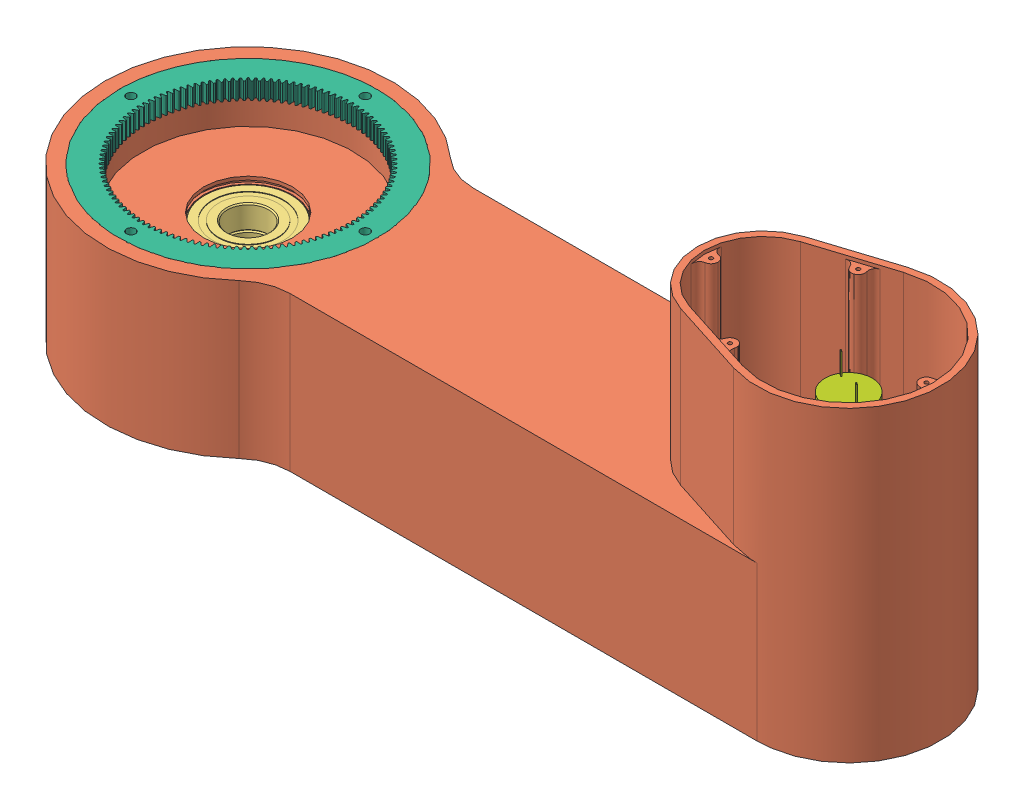
SolidWorks assembly Wall Link Assembly, configuration Default. Lengths in mm.
Overall size (388.62 146.05 133.35).
31 component instances, 11 part files, 33 mates.
Components (placement in the parent):
- magnet holder-1: magnet holder [Default] at (-69.5408 -3.8692 23.5746) x (-0.081084 0 0.996707) z (-0.996707 0 -0.081084) size (50.8 63.9 50.6)
- Wall Link Frame-1: Wall Link Frame [Default] at (-348.6164 39.6281 19.5878) x (1 0 0) z (0 -1 0) size (388.62 133.35 142.88)
- Bearing - .750-1: Bearing - .750 [3760T241] at (-69.2164 21.7681 19.5878) x (0.982823 0 0.184551) z (0 -1 0) size (41.27 41.27 11.11)
- Bearing - .750-2: Bearing - .750 [3760T241] at (-69.2164 32.8806 19.5878) x (0.837169 0 0.546944) z (0 1 0) size (41.27 41.27 11.11)
- Bearing - .750-3: Bearing - .750 [3760T241] at (-348.6164 6.5421 19.5878) x (0.79819 0 0.602406) z (0 1 0) size (41.27 41.27 11.11)
- Bearing - .750-4: Bearing - .750 [3760T241] at (-348.6164 17.6546 19.5878) x (0.713431 0 0.700725) z (0 1 0) size (41.27 41.27 11.11)
- Magnet Encoders E3-X-750-X-H-D-X-1: Magnet Encoders E3-X-750-X-H-D-X [Default] at (-69.2164 52.5821 19.5878) x (0 0 1) z (-1 0 0) size (55.98 16.26 66.52)
- EM237 Magnet-1: EM237 Magnet [Default] at (-69.2164 -16.3787 19.5878) x (0.767455 0 -0.641103) z (-0.641103 0 -0.767455) size (60.08 25.02 60.08)
- Ring Gear-1: Ring Gear [Default] at (-348.6168 41.9781 19.5878) x (0 -1 0) z (0 0 1) size (8 120 120)
- Magnet Encoders E3-X-750-X-H-D-X-2: Magnet Encoders E3-X-750-X-H-D-X [Default] at (-348.6164 -5.6182 19.5878) x (0 0 1) z (1 0 0) size (55.98 16.26 66.52)
- Slip Ring M322M1-0202-1: Slip Ring M322M1-0202 [Default] at (-69.2164 73.1741 19.5878) x (0.866025 0 0.5) z (0 -1 0) size (44 44 57)
- M5 Nylon Spacer-1: M5 Nylon Spacer [93657A042] at (-60.4664 67.7741 34.7433) x (0.837169 0 0.546944) z (0 -1 0) size (8 8 6)
- M5 Nylon Spacer-2: M5 Nylon Spacer [93657A042] at (-60.4664 67.7741 4.4324) x (0.552857 0 0.833276) z (0 -1 0) size (8 8 6)
- M5 Nylon Spacer-3: M5 Nylon Spacer [93657A042] at (-86.7164 67.7741 19.5878) x (0.837169 0 0.546944) z (0 -1 0) size (8 8 6)
- PCB_Battery Assembly-1: PCB_Battery Assembly [Default] at (-108.4133 -78.6819 -2.0435) size (127.38 21.9 77.22)
  - Battery PCB-1: Battery PCB [Default] at (-148.3186 115.135 -16.9005) x (1 0 0) z (0 -1 0) size (127.38 77.06 1.59)
  - Battery Assembly-1: Battery Assembly [Default] at (-101.6605 145.5711 -35.2548) x (-1 0 0) z (0 0 1) size (20.65 21.9 77.14)
    - Battery Holder - keystone-PN1043-1: Battery Holder - keystone-PN1043 [Default] at (27.979 42.1729 59.6018) size (20.65 18.93 77.14)
    - battery_6612-1: battery_6612 [Default] at (36.333 41.1675 88.8909) x (1 0 0) z (0 1 0) size (18.3 65.05 18.3)
  - Battery Assembly-2: Battery Assembly [Default] at (-130.4862 145.5711 78.5174) x (1 0 0) z (0 0 -1) size (20.65 21.9 77.14)
    - Battery Holder - keystone-PN1043-1: Battery Holder - keystone-PN1043 [Default] at (27.979 42.1729 59.6018) size (20.65 18.93 77.14)
    - battery_6612-1: battery_6612 [Default] at (36.333 41.1675 88.8909) x (1 0 0) z (0 1 0) size (18.3 65.05 18.3)
  - Battery Assembly-3: Battery Assembly [Default] at (-13.9797 145.5711 -35.2548) x (-1 0 0) z (0 0 1) size (20.65 21.9 77.14)
    - Battery Holder - keystone-PN1043-1: Battery Holder - keystone-PN1043 [Default] at (27.979 42.1729 59.6018) size (20.65 18.93 77.14)
    - battery_6612-1: battery_6612 [Default] at (36.333 41.1675 88.8909) x (1 0 0) z (0 1 0) size (18.3 65.05 18.3)
  - Battery Assembly-4: Battery Assembly [Default] at (-108.566 145.5711 78.5174) x (1 0 0) z (0 0 -1) size (20.65 21.9 77.14)
    - Battery Holder - keystone-PN1043-1: Battery Holder - keystone-PN1043 [Default] at (27.979 42.1729 59.6018) size (20.65 18.93 77.14)
    - battery_6612-1: battery_6612 [Default] at (36.333 41.1675 88.8909) x (1 0 0) z (0 1 0) size (18.3 65.05 18.3)
  - Battery Assembly-5: Battery Assembly [Default] at (-79.7403 145.5711 -35.2548) x (-1 0 0) z (0 0 1) size (20.65 21.9 77.14)
    - Battery Holder - keystone-PN1043-1: Battery Holder - keystone-PN1043 [Default] at (27.979 42.1729 59.6018) size (20.65 18.93 77.14)
    - battery_6612-1: battery_6612 [Default] at (36.333 41.1675 88.8909) x (1 0 0) z (0 1 0) size (18.3 65.05 18.3)
Mates (geometry in assembly coordinates):
- Concentric2: concentric anti-aligned: line of Wall Link Frame-1 through (-69.2164 -25.7134 19.5878) axis (0 1 0); cylinder of Bearing - .750-1 through (-69.2164 16.2118 19.5878) axis (0 -1 0) radius 9.525
- Coincident1: coincident aligned: plane of Wall Link Frame-1 through (-348.6164 16.2118 19.5878) normal (0 -1 0); plane of Bearing - .750-1 through (-72.9226 16.2118 39.3247) normal (0 -1 0)
- Concentric3: concentric aligned: line of Wall Link Frame-1 through (-69.2164 -25.7134 19.5878) axis (0 1 0); cylinder of Bearing - .750-2 through (-69.2164 38.4368 19.5878) axis (0 1 0) radius 9.525
- Coincident2: coincident anti-aligned: plane of Bearing - .750-1 through (-72.9226 27.3243 39.3247) normal (0 1 0); plane of Bearing - .750-2 through (-58.2328 27.3243 2.7759) normal (0 -1 0)
- Concentric4: concentric anti-aligned: cylinder of magnet holder-1 through (-69.2164 -3.8692 19.5878) axis (0 -1 0) radius 9.525; cylinder of Bearing - .750-2 through (-69.2164 38.4368 19.5878) axis (0 1 0) radius 9.525
- Coincident3: coincident anti-aligned: plane of magnet holder-1 through (-70.2462 16.2118 32.246) normal (0 1 0); plane of Wall Link Frame-1 through (-348.6164 16.2118 19.5878) normal (0 -1 0)
- Concentric5: concentric aligned: line of Wall Link Frame-1 through (-69.2164 -25.7134 19.5878) axis (0 1 0); cylinder of Magnet Encoders E3-X-750-X-H-D-X-1 through (-69.2164 59.1353 19.5878) axis (0 1 0) radius 9.5263
- Concentric6: concentric anti-aligned: cylinder of Wall Link Frame-1 through (-69.2164 49.1531 42.6002) axis (0 1 0) radius 1.1303; cylinder of Magnet Encoders E3-X-750-X-H-D-X-1 through (-69.2164 52.5821 42.6002) axis (0 -1 0) radius 1.4351
- Coincident7: coincident anti-aligned: plane of Wall Link Frame-1 through (-348.6164 49.1531 19.5878) normal (0 1 0); plane of Magnet Encoders E3-X-750-X-H-D-X-1 through (-69.2164 49.1531 19.5878) normal (0 -1 0)
- Coincident8: coincident anti-aligned: plane of magnet holder-1 through (-69.5408 -3.8692 23.5746) normal (0 -1 0); plane of EM237 Magnet-1 through (-69.2164 -3.8692 19.5878) normal (0 1 0)
- Concentric7: concentric aligned: line of Wall Link Frame-1 through (-69.2164 -25.7134 19.5878) axis (0 1 0); cylinder of EM237 Magnet-1 through (-69.2164 -3.8692 19.5878) axis (0 1 0) radius 3.4036
- Coincident9: coincident anti-aligned: line of Wall Link Frame-1 through (-348.6164 -48.2167 19.5878) axis (0 1 0); line of Ring Gear-1 through (-348.6168 45.9781 19.5878) axis (0 -1 0)
- Coincident10: coincident anti-aligned: plane of Wall Link Frame-1 through (-348.6164 37.9781 19.5878) normal (0 1 0); plane of Ring Gear-1 through (-348.6168 37.9781 19.5878) normal (0 -1 0)
- Concentric8: concentric anti-aligned: cylinder of Wall Link Frame-1 through (-294.1114 37.9781 19.5878) axis (0 1 0) radius 1.7272; cylinder of Ring Gear-1 through (-294.1114 45.9781 19.5878) axis (0 -1 0) radius 2.0828
- Coincident11: coincident anti-aligned: plane of Wall Link Frame-1 through (-369.2539 0.9858 19.5878) normal (0 1 0); plane of Bearing - .750-3 through (-336.519 0.9858 3.5587) normal (0 -1 0)
- Concentric9: concentric aligned: line of Wall Link Frame-1 through (-348.6164 -48.2167 19.5878) axis (0 1 0); cylinder of Bearing - .750-3 through (-348.6164 12.0983 19.5878) axis (0 1 0) radius 9.525
- Concentric10: concentric aligned: cylinder of Bearing - .750-4 through (-348.6164 23.2108 19.5878) axis (0 1 0) radius 9.525; line of Wall Link Frame-1 through (-348.6164 -48.2167 19.5878) axis (0 1 0)
- Coincident13: coincident anti-aligned: plane of Bearing - .750-3 through (-336.519 12.0983 3.5587) normal (0 1 0); plane of Bearing - .750-4 through (-334.5446 12.0983 5.2608) normal (0 -1 0)
- Coincident14: coincident anti-aligned: plane of Wall Link Frame-1 through (-364.4914 -2.1892 19.5878) normal (0 -1 0); plane of Magnet Encoders E3-X-750-X-H-D-X-2 through (-348.6164 -2.1892 19.5878) normal (0 1 0)
- Concentric12: concentric anti-aligned: cylinder of Wall Link Frame-1 through (-348.6164 -2.1892 42.6002) axis (0 -1 0) radius 1.1303; cylinder of Magnet Encoders E3-X-750-X-H-D-X-2 through (-348.6164 -5.6182 42.6002) axis (0 1 0) radius 1.4351
- Concentric13: concentric anti-aligned: cylinder of Wall Link Frame-1 through (-348.6164 -2.1892 -3.4246) axis (0 -1 0) radius 1.1303; cylinder of Magnet Encoders E3-X-750-X-H-D-X-2 through (-348.6164 -5.6182 -3.4246) axis (0 1 0) radius 1.4351
- Concentric14: concentric aligned: cylinder of magnet holder-1 through (-69.2164 -3.8692 19.5878) axis (0 -1 0) radius 6.7469; cylinder of Slip Ring M322M1-0202-1 through (-69.2164 93.7741 19.5878) axis (0 -1 0) radius 11
- Concentric15: concentric aligned: cylinder of Magnet Encoders E3-X-750-X-H-D-X-1 through (-86.7164 64.7741 19.5878) axis (0 1 0) radius 2.1; cylinder of M5 Nylon Spacer-3 through (-86.7164 64.7741 19.5878) axis (0 1 0) radius 2.65
- Concentric16: concentric aligned: cylinder of Magnet Encoders E3-X-750-X-H-D-X-1 through (-60.4664 64.7741 34.7433) axis (0 1 0) radius 2.1; cylinder of M5 Nylon Spacer-1 through (-60.4664 64.7741 34.7433) axis (0 1 0) radius 2.65
- Concentric17: concentric aligned: cylinder of Magnet Encoders E3-X-750-X-H-D-X-1 through (-60.4664 64.7741 4.4324) axis (0 1 0) radius 2.1; cylinder of M5 Nylon Spacer-2 through (-60.4664 64.7741 4.4324) axis (0 1 0) radius 2.65
- Coincident16: coincident anti-aligned: plane of Magnet Encoders E3-X-750-X-H-D-X-1 through (-69.2164 64.7741 19.5878) normal (0 1 0); plane of M5 Nylon Spacer-2 through (-60.4664 64.7741 4.4324) normal (0 -1 0)
- Coincident17: coincident anti-aligned: plane of Magnet Encoders E3-X-750-X-H-D-X-1 through (-69.2164 64.7741 19.5878) normal (0 1 0); plane of M5 Nylon Spacer-1 through (-60.4664 64.7741 34.7433) normal (0 -1 0)
- Coincident18: coincident anti-aligned: plane of Magnet Encoders E3-X-750-X-H-D-X-1 through (-69.2164 64.7741 19.5878) normal (0 1 0); plane of M5 Nylon Spacer-3 through (-86.7164 64.7741 19.5878) normal (0 -1 0)
- Concentric19: concentric aligned: cylinder of Magnet Encoders E3-X-750-X-H-D-X-1 through (-86.7164 64.7741 19.5878) axis (0 1 0) radius 2.1; cylinder of Slip Ring M322M1-0202-1 through (-86.7164 73.1741 19.5878) axis (0 1 0) radius 2.75
- Coincident19: coincident anti-aligned: plane of Slip Ring M322M1-0202-1 through (-50.1639 70.7741 30.5878) normal (0 -1 0); plane of M5 Nylon Spacer-3 through (-86.7164 70.7741 19.5878) normal (0 1 0)
- Concentric20: concentric anti-aligned: cylinder of Wall Link Frame-1 through (-142.0509 36.4531 51.7696) axis (0 -1 0) radius 0.889; cylinder of PCB_Battery Assembly-1/Battery PCB-1 through (-142.0509 34.8656 51.7696) axis (0 1 0) radius 1.651
- Concentric23: concentric anti-aligned: cylinder of Wall Link Frame-1 through (-263.0819 36.4531 51.7696) axis (0 -1 0) radius 0.889; cylinder of PCB_Battery Assembly-1/Battery PCB-1 through (-263.0819 34.8656 51.7696) axis (0 1 0) radius 1.651
- Coincident21: coincident anti-aligned: plane of Wall Link Frame-1 through (-348.6164 36.4531 19.5878) normal (0 -1 0); plane of PCB_Battery Assembly-1/Battery PCB-1 through (-256.7319 36.4531 -18.944) normal (0 1 0)
